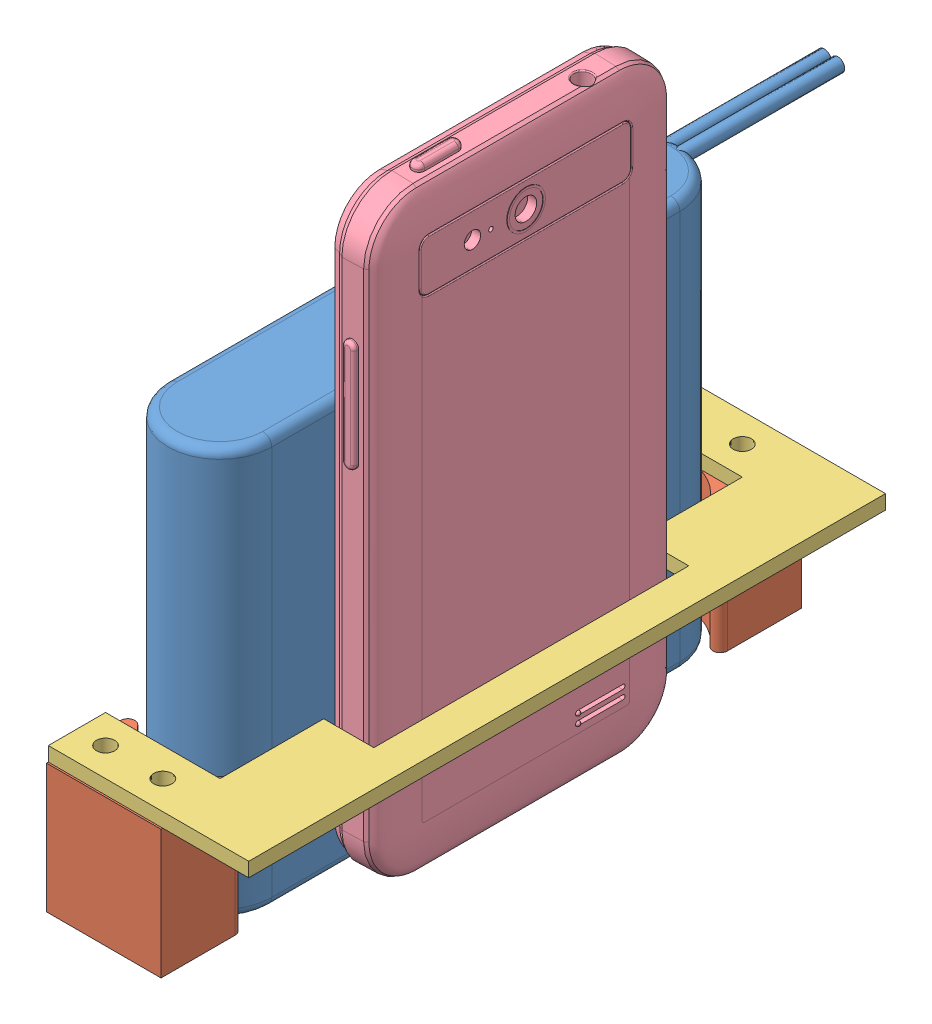
SolidWorks assembly CH_ASSEM_BatteryPhone, configuration Default. Lengths in mm.
Overall size (44.45 133.58 161.51).
5 component instances, 4 part files, 12 mates.
Components (placement in the parent):
- PART_BatterySlim12V-1: PART_BatterySlim12V [Default] at (26.3058 77.0384 64.08) x (0 -1 0) z (0 0 1) size (90.56 23.03 147.25)
- PART_SlimBatteryClip-1: PART_SlimBatteryClip [Default] at (39.0058 31.7884 107.3076) x (0 0 -1) z (1 0 0) size (18.01 28.57 25.4)
- PART_SlimBatteryClip-2: PART_SlimBatteryClip [Default] at (13.6058 31.7884 20.8523) x (0 0 1) z (-1 0 0) size (18.01 28.57 25.4)
- PART_PhoneSupportSheet-1: PART_PhoneSupportSheet [Default] at (58.0558 60.3634 134.692) x (0 0 -1) z (1 0 0) size (141.22 3.17 44.45)
- PART_ZTESpeed-1: PART_ZTESpeed [Default] at (40.0121 98.6181 70.154) x (0 0 1) z (-1 0 0) size (68.17 133.58 10.49)
Mates (geometry in assembly coordinates):
- Coincident1: coincident aligned: plane of PART_BatterySlim12V-1 through (26.3058 -1.8983 64.08) normal (0 -1 0); plane of PART_SlimBatteryClip-1 through (39.0058 -1.8983 107.3076) normal (0 -1 0)
- Coincident2: coincident aligned: plane of PART_BatterySlim12V-1 through (26.3058 -1.8983 64.08) normal (0 -1 0); plane of PART_SlimBatteryClip-2 through (13.6058 -1.8983 20.8523) normal (0 -1 0)
- Concentric3: concentric aligned: cylinder of PART_SlimBatteryClip-1 through (19.9558 26.6767 128.342) axis (0 -1 0) radius 2.032; cylinder of PART_PhoneSupportSheet-1 through (19.9558 29.8517 128.342) axis (0 -1 0) radius 2.032
- Concentric4: concentric aligned: cylinder of PART_SlimBatteryClip-1 through (32.6558 26.6767 128.342) axis (0 -1 0) radius 2.032; cylinder of PART_PhoneSupportSheet-1 through (32.6558 29.8517 128.342) axis (0 -1 0) radius 2.032
- Coincident7: coincident anti-aligned: plane of PART_SlimBatteryClip-2 through (13.6058 26.6767 20.8523) normal (0 1 0); plane of PART_PhoneSupportSheet-1 through (58.0558 26.6767 134.692) normal (0 -1 0)
- Concentric5: concentric aligned: cylinder of PART_SlimBatteryClip-2 through (32.6558 26.6767 -0.182) axis (0 -1 0) radius 2.032; cylinder of PART_PhoneSupportSheet-1 through (32.6558 29.8517 -0.182) axis (0 -1 0) radius 2.032
- Concentric6: concentric aligned: cylinder of PART_SlimBatteryClip-2 through (19.9558 26.6767 -0.182) axis (0 -1 0) radius 2.032; cylinder of PART_PhoneSupportSheet-1 through (19.9558 29.8517 -0.182) axis (0 -1 0) radius 2.032
- Symmetric1: symmetric aligned: plane of PART_BatterySlim12V-1 through (26.3058 43.3517 64.08) normal (0 0 1); plane of PART_SlimBatteryClip-2 through (13.6058 26.6767 -6.9289) normal (0 0 -1); plane of PART_SlimBatteryClip-1 through (39.0058 26.6767 135.0888) normal (0 0 1)
- Width2: width anti-aligned: plane of PART_SlimBatteryClip-1 through (13.6058 26.6767 107.3076) normal (-1 0 0); plane of PART_SlimBatteryClip-1 through (39.0058 26.6767 107.3076) normal (1 0 0); plane of PART_BatterySlim12V-1 through (37.8058 43.3517 18.83) normal (1 0 0); plane of PART_BatterySlim12V-1 through (14.8058 43.3517 109.33) normal (-1 0 0)
- Width3: width aligned: plane of PART_PhoneSupportSheet-1 through (58.0558 63.5384 29.155) normal (0 0 1); plane of PART_PhoneSupportSheet-1 through (58.0558 63.5384 99.005) normal (0 0 -1); plane of PART_ZTESpeed-1 through (46.3733 152.8884 30.6369) normal (0.033526 0 -0.999438); plane of PART_ZTESpeed-1 through (46.3733 152.8884 97.523) normal (0.033526 0 0.999438)
- Width4: width anti-aligned: plane of PART_BatterySlim12V-1 through (37.8058 77.0384 18.83) normal (1 0 0); plane of PART_PhoneSupportSheet-1 through (50.1183 63.5384 134.692) normal (-1 0 0); plane of PART_ZTESpeed-1 through (39.0121 152.8884 86.58) normal (-1 0 0); plane of PART_ZTESpeed-1 through (48.9121 42.8884 86.58) normal (1 0 0)
- Coincident8: coincident: plane of PART_BatterySlim12V-1 through (26.3058 31.7884 64.08) normal (0 -1 0); line of PART_ZTESpeed-1 through (41.6947 31.7884 86.58) axis (0 0 -1)
